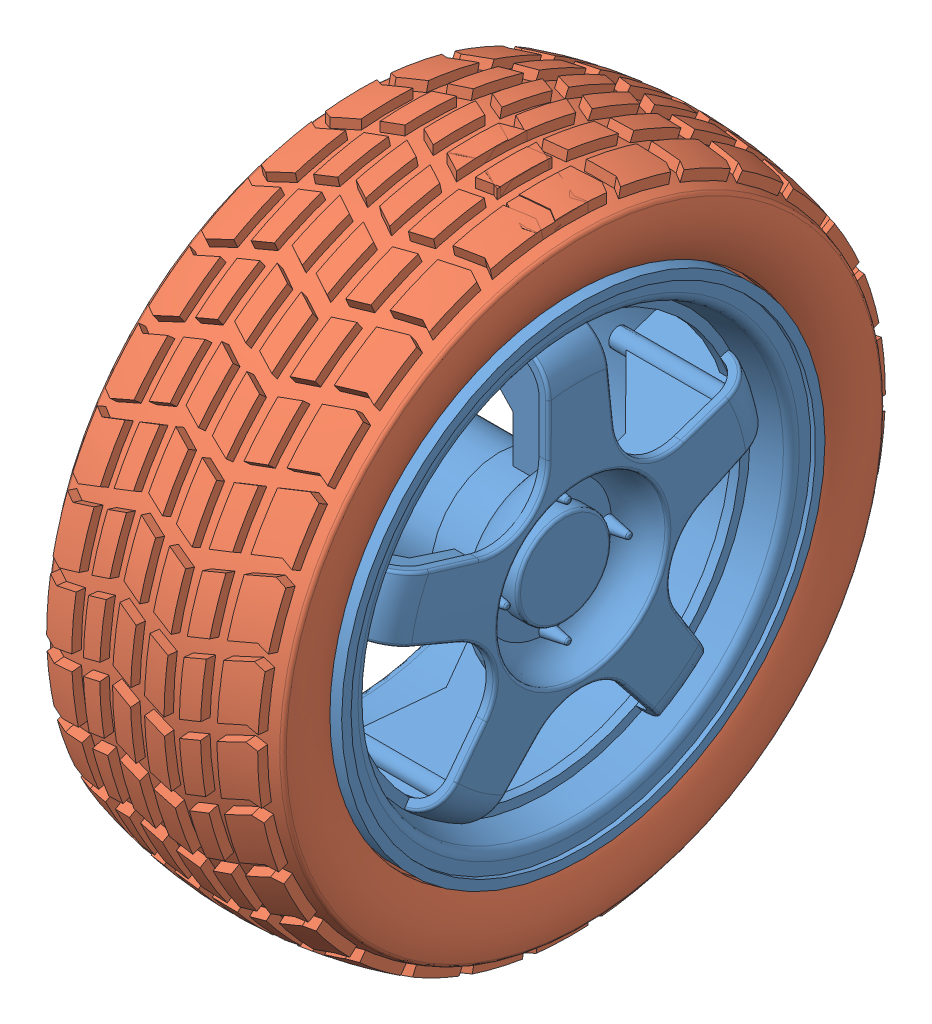
SolidWorks assembly Toy Wheel, configuration Default. Lengths in mm.
Overall size (27.3 69.99 70.09).
2 component instances, 2 part files, 2 mates.
Components (placement in the parent):
- Rim-1: Rim [Default] at (12.0157 26.258 44.0435) size (27.3 51.5 51.5)
- Tyre-1: Tyre [Default] at (12.3157 26.258 44.0435) size (25.56 69.99 70.09)
Mates (geometry in assembly coordinates):
- Coincident1: coincident anti-aligned: plane of Rim-1 through (22.8157 50.008 44.0435) normal (-1 0 0); plane of Tyre-1 through (22.8157 26.258 44.0435) normal (1 0 0)
- Concentric1: concentric aligned: circle of Rim-1; circle of Tyre-1
